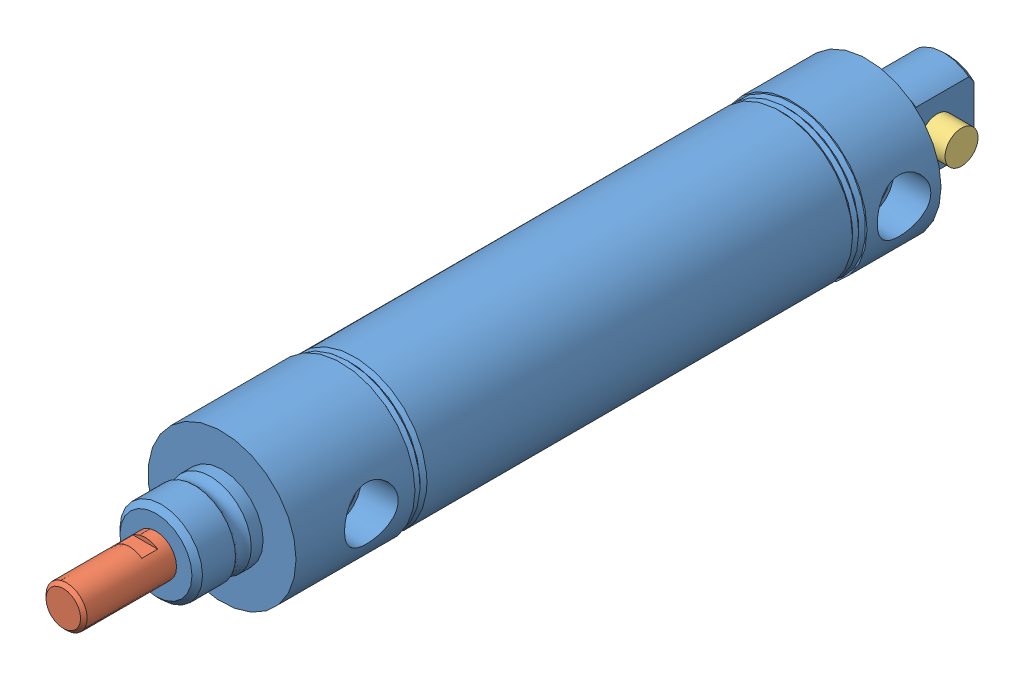
SolidWorks assembly A17020DP, configuration Default. Lengths in mm.
Overall size (28.45 28.45 170.2).
3 component instances, 3 part files, 4 mates.
Components (placement in the parent):
- A17020DP-MainBody-1: A17020DP-MainBody [Default] x (0 0 -1) z (1 0 0) size (152.4 28.45 28.45)
- A17020DP-Rod-1: A17020DP-Rod [Default] at (0 0 680.8565) x (0 0 -1) z (-0.999884 -0.015234 0) size (122.17 26.99 26.99)
- A17020DP-PIN-1: A17020DP-PIN [Default] at (0 0 -148.336) x (0 0 -1) z (1 0 0) size (6.35 6.35 19.05)
Mates (geometry in assembly coordinates):
- LimitDistance1: limit distance = 2.0559 mm: plane of A17020DP-MainBody-1 through (0 0 -109.474) normal (0 0 1); plane of A17020DP-Rod-1 through (0 0 -107.4181) normal (0 0 -1)
- Concentric1: concentric anti-aligned: cylinder of A17020DP-MainBody-1 through (0 0 0) axis (0 0 -1) radius 3.9624; cylinder of A17020DP-Rod-1 through (0 0 -118.6255) axis (0 0 1) radius 3.9624
- Concentric2: concentric: cylinder of A17020DP-MainBody-1 through (-14.224 0 -148.336) axis (1 0 0) radius 3.175; cylinder of A17020DP-PIN-1 through (9.525 0 -148.336) axis (-1 0 0) radius 3.175
- Width1: width anti-aligned: plane of A17020DP-PIN-1 through (9.525 0 -148.336) normal (1 0 0); plane of A17020DP-PIN-1 through (-9.525 0 -148.336) normal (-1 0 0); plane of A17020DP-MainBody-1 through (-4.826 6.3019 -126.7179) normal (-1 0 0); plane of A17020DP-MainBody-1 through (4.826 -6.3019 -126.7179) normal (1 0 0)
